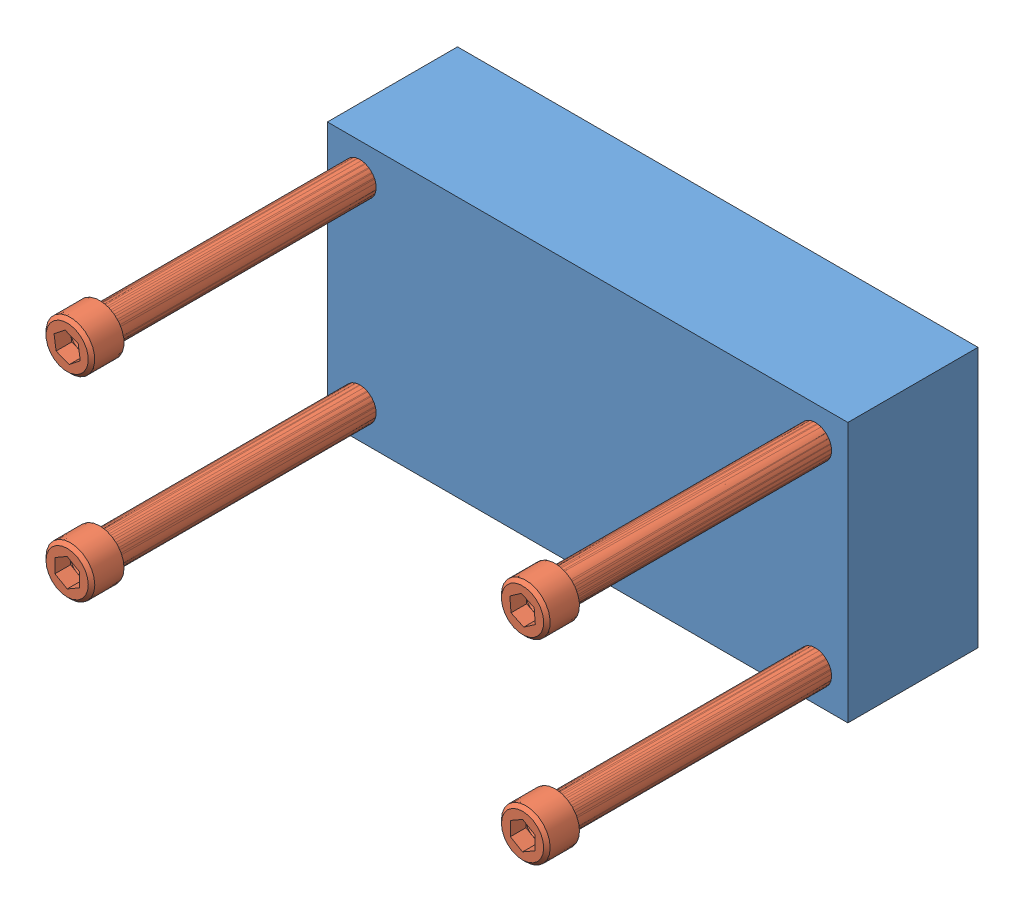
SolidWorks assembly Placa_Tornillo, configuration Default. Lengths in mm.
Overall size (101.6 50.8 82.55).
5 component instances, 2 part files, 5 mates.
Components (placement in the parent):
- Base-1: Base [Default] at (45.9358 46.0021 78.5274) size (101.6 50.8 25.4)
- socket head cap screw_ai-1: socket head cap screw_ai [HX-SHCS 0.25-20x3x1-C] at (1.4858 65.0521 135.6774) x (0 0 -1) z (-0.989335 -0.14566 0) size (82.55 9.53 9.53)
- socket head cap screw_ai-2: socket head cap screw_ai [HX-SHCS 0.25-20x3x1-C] at (90.3858 65.0521 135.6774) x (0 0 -1) z (0.426192 0.904633 0) size (82.55 9.53 9.53)
- socket head cap screw_ai-3: socket head cap screw_ai [HX-SHCS 0.25-20x3x1-C] at (1.4858 26.9521 135.6774) x (0 0 -1) z (1 0 0) size (82.55 9.53 9.53)
- socket head cap screw_ai-4: socket head cap screw_ai [HX-SHCS 0.25-20x3x1-C] at (90.3858 26.9521 135.6774) x (0 0 -1) z (1 0 0) size (82.55 9.53 9.53)
Mates (geometry in assembly coordinates):
- Concéntrica1: concentric aligned: circle of Base-1; circle of socket head cap screw_ai-1
- Concéntrica2: concentric aligned: circle of Base-1; circle of socket head cap screw_ai-2
- Concéntrica3: concentric aligned: circle of Base-1; circle of socket head cap screw_ai-3
- Concéntrica4: concentric aligned: circle of Base-1; circle of socket head cap screw_ai-4
- Coincidente10: coincident: plane of Base-1 through (45.9358 46.0021 53.1274) normal (0 0 -1); plane of socket head cap screw_ai-2 through (88.1972 66.0832 53.1274) normal (0 0 -1)
